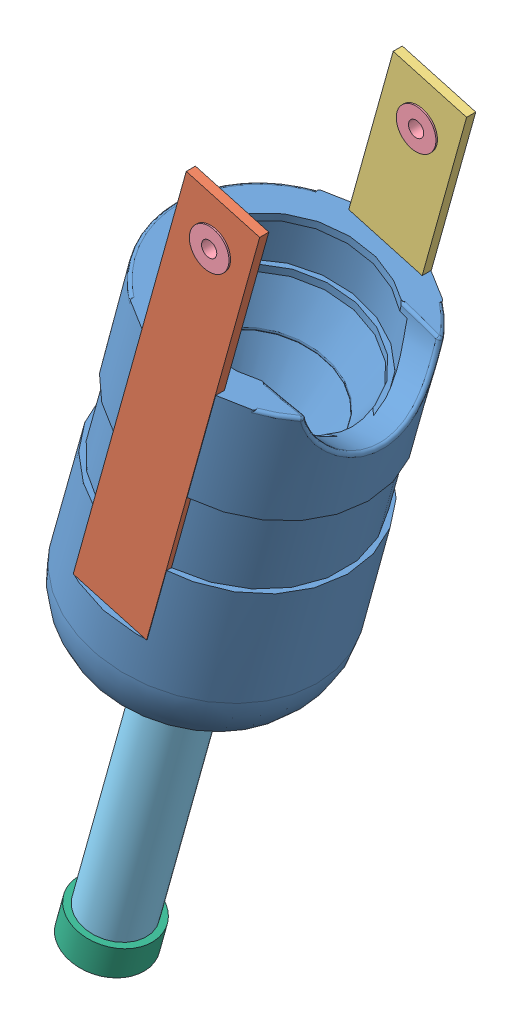
SolidWorks assembly parte inferior, configuration Predeterminado. Lengths in mm.
Overall size (217.56 542.05 150).
7 component instances, 6 part files, 14 mates.
Components (placement in the parent):
- Copa inf-1: Copa inf [Default] at (132.7528 214.6197 389.5102) x (0 1 0) z (0 0 1) size (264.24 192.85 150)
- lateral 1-1: lateral 1 [Predeterminado] at (24.973 28.4964 404.5102) x (0.963212 -0.268742 0) z (0 0 1) size (50 276 106)
- lateral 2-1: lateral 2 [Predeterminado] at (26.3225 34.3491 374.5102) x (-0.963212 0.268742 0) z (0 0 -1) size (50 270 106)
- rodamiento-3: rodamiento [Predeterminado] at (91.0835 265.4466 453.5102) x (-0.461493 -0.887144 0) z (0 0 1) size (26 26 8)
- rodamiento-4: rodamiento [Predeterminado] at (90.8205 265.52 317.5102) x (-0.767728 -0.640776 0) z (0 0 1) size (26 26 8)
- Eje-2: Eje [Predeterminado] at (24.8435 28.5325 389.5102) x (-0.180563 0.050378 -0.982272) z (-0.946137 0.263978 0.187459) size (42 250 42)
- caucho-1: caucho [Predeterminado] at (-47.7168 -231.5348 389.5102) x (0.780651 -0.217806 0.585786) z (-0.564236 0.157425 0.810466) size (50 100 50)
Mates (geometry in assembly coordinates):
- Coincidente1: coincident anti-aligned: plane of Copa inf-1 through (76.7897 14.0393 354.5102) normal (0.268742 0.963212 0); plane of lateral 1-1 through (24.973 28.4964 404.5102) normal (-0.268742 -0.963212 0)
- Coincidente3: coincident anti-aligned: plane of Copa inf-1 through (132.7528 214.6197 354.5102) normal (0 0 1); plane of lateral 1-1 through (2.5051 40.9942 354.5102) normal (0 0 -1)
- Coincidente4: coincident anti-aligned: plane of Copa inf-1 through (56.8558 235.7954 454.5102) normal (0.963212 -0.268742 0); plane of lateral 1-1 through (2.5051 40.9942 454.5102) normal (-0.963212 0.268742 0)
- Coincidente5: coincident anti-aligned: plane of Copa inf-1 through (78.4022 19.8185 424.5102) normal (0.268742 0.963212 0); plane of lateral 2-1 through (26.3225 34.3491 374.5102) normal (-0.268742 -0.963212 0)
- Coincidente6: coincident anti-aligned: plane of Copa inf-1 through (132.7528 214.6197 424.5102) normal (0 0 -1); plane of lateral 2-1 through (52.0152 33.4098 424.5102) normal (0 0 1)
- Coincidente7: coincident anti-aligned: plane of Copa inf-1 through (56.5928 235.8688 324.5102) normal (0.963212 -0.268742 0); plane of lateral 2-1 through (3.8546 46.8469 324.5102) normal (-0.963212 0.268742 0)
- Concéntrica3: concentric anti-aligned: cylinder of lateral 1-1 through (91.0835 265.4466 354.5102) axis (0 0 1) radius 13; cylinder of rodamiento-3 through (91.0835 265.4466 461.5102) axis (0 0 -1) radius 13
- Distancia3: distance = 1 mm aligned: plane of rodamiento-3 through (91.0835 265.4466 453.5102) normal (0 0 -1); plane of lateral 1-1 through (99.1457 294.343 454.5102) normal (0 0 -1)
- Concéntrica4: concentric aligned: cylinder of lateral 2-1 through (90.8205 265.52 424.5102) axis (0 0 -1) radius 13; cylinder of rodamiento-4 through (90.8205 265.52 325.5102) axis (0 0 -1) radius 13
- Distancia4: distance = 1 mm aligned: plane of rodamiento-4 through (90.8205 265.52 317.5102) normal (0 0 -1); plane of lateral 2-1 through (98.8828 294.4164 318.5102) normal (0 0 -1)
- Coincidente8: coincident anti-aligned: plane of lateral 1-1 through (24.973 28.4964 404.5102) normal (-0.268742 -0.963212 0); plane of Eje-2 through (24.8435 28.5325 389.5102) normal (0.268742 0.963212 0)
- Concéntrica5: concentric anti-aligned: cylinder of Copa inf-1 through (49.9187 118.406 389.5102) axis (-0.268742 -0.963212 0) radius 21; cylinder of Eje-2 through (-42.3419 -212.2705 389.5102) axis (0.268742 0.963212 0) radius 21
- Concéntrica6: concentric anti-aligned: cylinder of Eje-2 through (-42.3419 -212.2705 389.5102) axis (0.268742 0.963212 0) radius 21; cylinder of caucho-1 through (-42.3419 -212.2705 389.5102) axis (-0.268742 -0.963212 0) radius 25
- Coincidente9: coincident anti-aligned: plane of Eje-2 through (-42.3419 -212.2705 389.5102) normal (-0.268742 -0.963212 0); plane of caucho-1 through (-42.3419 -212.2705 389.5102) normal (0.268742 0.963212 0)
